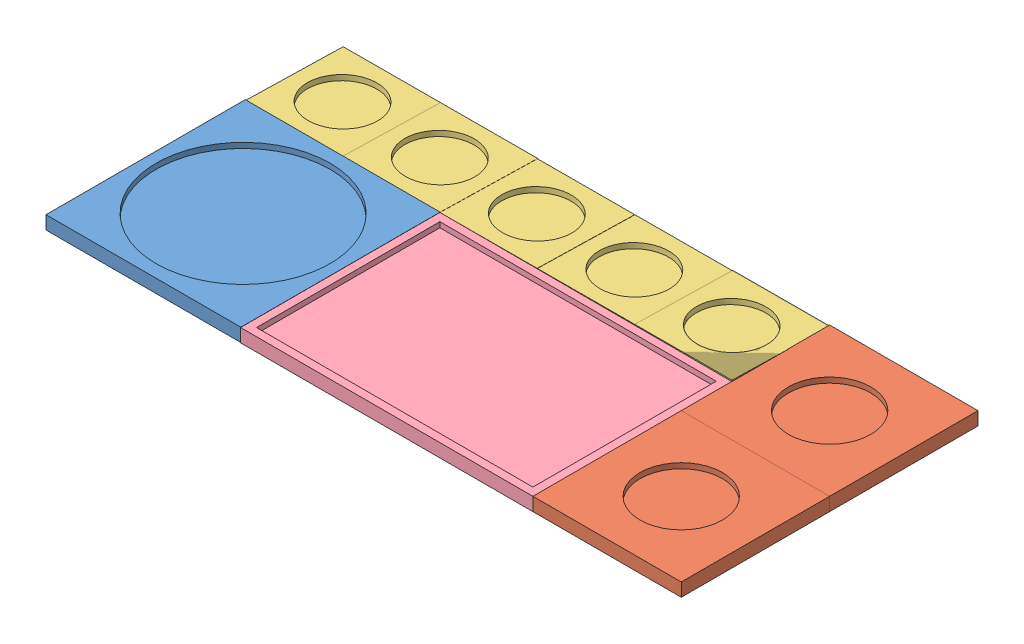
SolidWorks assembly Piece Assembly, configuration Default. Lengths in mm.
Overall size (239.17 6.52 111.87).
10 component instances, 4 part files, 2 mates.
Components (placement in the parent):
- Large_model_Piece-2: Large_model_Piece [Default] at (63.9641 37.7585 115.873) size (73.33 5 75)
- medium_model_Piece-2: medium_model_Piece [Default] at (218.1136 37.7043 87.2836) size (55.83 5 55.83)
- Small_model_Piece-2: Small_model_Piece [Default] at (173.9847 38.1619 41.0825) x (0.99999 0.004183 0.001464) z (-0.001555 0.021922 0.999758) size (36.67 5 36.67)
- vehicle_model_Piece-2: vehicle_model_Piece [Default] at (113.7988 37.7043 60.7942) size (110 5 75)
- Small_model_Piece-3: Small_model_Piece [Default] at (174.0615 38.166 41.2534) x (0.99999 0.004183 0.001464) z (-0.001555 0.021922 0.999758) size (36.67 5 36.67)
- Small_model_Piece-4: Small_model_Piece [Default] at (137.3951 38.0126 41.1997) x (0.99999 0.004183 0.001464) z (-0.001555 0.021922 0.999758) size (36.67 5 36.67)
- Small_model_Piece-5: Small_model_Piece [Default] at (100.6514 37.8589 41.1459) x (0.99999 0.004183 0.001464) z (-0.001555 0.021922 0.999758) size (36.67 5 36.67)
- medium_model_Piece-3: medium_model_Piece [Default] at (218.1136 37.7043 31.4503) size (55.83 5 55.83)
- Small_model_Piece-6: Small_model_Piece [Default] at (27.3186 37.6064 40.929) x (0.99999 0.004183 0.001464) z (-0.001555 0.021922 0.999758) size (36.67 5 36.67)
- Small_model_Piece-10: Small_model_Piece [Default] at (63.9849 37.7597 40.9826) x (0.99999 0.004183 0.001464) z (-0.001555 0.021922 0.999758) size (36.67 5 36.67)
Mates (geometry in assembly coordinates):
- Coincident27: coincident: point of Large_model_Piece-2; point of Small_model_Piece-10
- Coincident28: coincident: point of Small_model_Piece-6; point of Small_model_Piece-10
